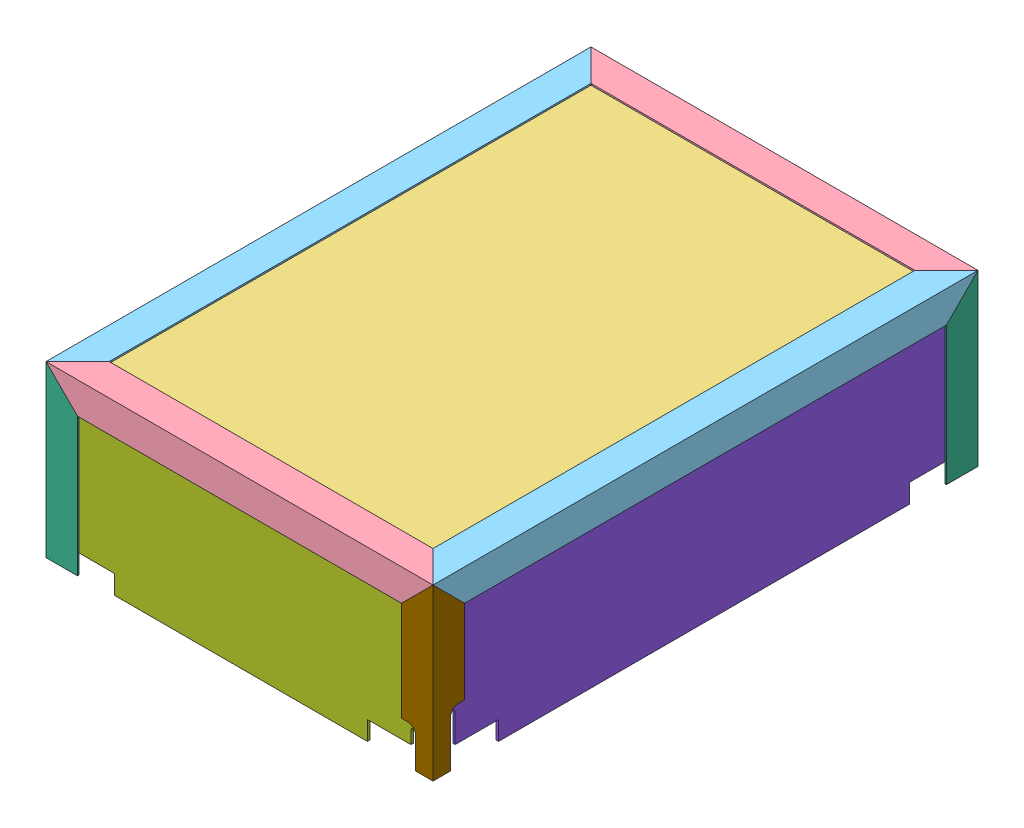
SolidWorks assembly couvercle, configuration Défaut. Lengths in mm.
Overall size (490 215 690).
13 component instances, 9 part files, 32 mates.
Components (placement in the parent):
- plaque_acrylique_680x210-2: plaque_acrylique_680x210 [Défaut] at (-694.8689 73.91 -173.3892) x (0 0 -1) z (1 0 0) size (680 210 3)
- plaque_acrylique_380x210-2: plaque_acrylique_380x210 [Défaut] at (-401.8689 73.91 -516.3892) size (480 210 3)
- plaque_acrylique_380x680-1: plaque_acrylique_380x680 [Défaut] at (-401.8689 178.91 -173.3892) x (1 0 0) z (0 1 0) size (480 680 3)
- eclisse_40x40x404_bisote_x2-1: eclisse_40x40x404_bisote_x2 [Défaut] at (-206.8689 163.7964 -498.3892) x (0 0 1) z (0 -1 0) size (40 490 40)
- eclisse_40x40x704_bisote_x2-1: eclisse_40x40x704_bisote_x2 [Défaut] at (-226.9825 163.91 -518.3892) x (0 -1 0) z (-1 0 0) size (40 690 40)
- eclisse_40x40x404_bisote_x2-2: eclisse_40x40x404_bisote_x2 [Défaut] at (-696.8689 163.7964 151.6108) x (0 0 -1) z (0 -1 0) size (40 490 40)
- eclisse_40x40x704_bisote_x2-2: eclisse_40x40x704_bisote_x2 [Défaut] at (-676.8689 163.7964 -518.3892) x (1 0 0) z (0 -1 0) size (40 690 40)
- eclisse_40x40x222_bisote_x1-1: eclisse_40x40x222_bisote_x1 [Défaut] at (-676.7552 183.91 -498.3892) x (0 0 1) z (1 0 0) size (40 215 40)
- eclisse_40x40x222_bisote_x1-2: eclisse_40x40x222_bisote_x1 [Défaut] at (-226.8689 183.91 -498.2755) x (-1 0 0) z (0 0 1) size (40 215 40)
- eclisse_40x40x222_bisote_x1-4: eclisse_40x40x222_bisote_x1 [Défaut] at (-676.8689 183.91 151.4972) x (1 0 0) z (0 0 -1) size (40 215 40)
- plaque_acrylique_380x210_Moteur-1: plaque_acrylique_380x210_Moteur [Défaut] at (-401.8689 73.91 166.6108) size (480 210 3)
- plaque_acrylique_680x210_moteur-1: plaque_acrylique_680x210_moteur [Défaut] at (-211.8689 73.91 -173.3892) x (0 0 -1) z (1 0 0) size (680 210 3)
- eclisse_40x40x222_bisote_x1_Moteur-1: eclisse_40x40x222_bisote_x1_Moteur [Défaut] at (-226.9825 183.91 151.6108) x (0 0 -1) z (-1 0 0) size (40 215 40)
Mates (geometry in assembly coordinates):
- Coïncidente1: coincident anti-aligned: plane of plaque_acrylique_380x680-1 through (-401.8689 181.91 -173.3892) normal (0 1 0); plane of eclisse_40x40x704_bisote_x2-1 through (-208.8689 181.91 171.6108) normal (0 -1 0)
- Coïncidente2: coincident anti-aligned: plane of eclisse_40x40x704_bisote_x2-1 through (-208.8689 181.91 171.6108) normal (-1 0 0); plane of plaque_acrylique_680x210_moteur-1 through (-208.8689 73.91 -173.3892) normal (1 0 0)
- Coïncidente3: coincident anti-aligned: plane of plaque_acrylique_380x210-2 through (-401.8689 73.91 -516.3892) normal (0 0 -1); plane of eclisse_40x40x404_bisote_x2-1 through (-696.8689 181.91 -516.3892) normal (0 0 1)
- Coïncidente4: coincident anti-aligned: plane of plaque_acrylique_380x680-1 through (-401.8689 181.91 -173.3892) normal (0 1 0); plane of eclisse_40x40x404_bisote_x2-1 through (-696.8689 181.91 -516.3892) normal (0 -1 0)
- Coïncidente5: coincident anti-aligned: plane of plaque_acrylique_680x210-2 through (-694.8689 73.91 -173.3892) normal (-1 0 0); plane of eclisse_40x40x704_bisote_x2-2 through (-694.8689 181.91 171.6108) normal (1 0 0)
- Coïncidente6: coincident anti-aligned: plane of plaque_acrylique_380x680-1 through (-401.8689 181.91 -173.3892) normal (0 1 0); plane of eclisse_40x40x704_bisote_x2-2 through (-694.8689 181.91 171.6108) normal (0 -1 0)
- Coïncidente7: coincident anti-aligned: plane of eclisse_40x40x404_bisote_x2-2 through (-206.8689 181.91 169.6108) normal (0 0 -1); plane of plaque_acrylique_380x210_Moteur-1 through (-401.8689 73.91 169.6108) normal (0 0 1)
- Coïncidente9: coincident anti-aligned: plane of plaque_acrylique_380x210_Moteur-1 through (-401.8689 73.91 169.6108) normal (0 0 1); plane of eclisse_40x40x222_bisote_x1_Moteur-1 through (-208.8689 -31.09 169.6108) normal (0 0 -1)
- Coïncidente10: coincident anti-aligned: plane of plaque_acrylique_680x210_moteur-1 through (-208.8689 73.91 -173.3892) normal (1 0 0); plane of eclisse_40x40x222_bisote_x1_Moteur-1 through (-208.8689 -31.09 169.6108) normal (-1 0 0)
- Coïncidente11: coincident anti-aligned: plane of plaque_acrylique_380x210-2 through (-401.8689 73.91 -516.3892) normal (0 0 -1); plane of eclisse_40x40x222_bisote_x1-2 through (-208.8689 -31.09 -516.3892) normal (0 0 1)
- Coïncidente12: coincident anti-aligned: plane of eclisse_40x40x222_bisote_x1-2 through (-208.8689 -31.09 -516.3892) normal (-1 0 0); plane of plaque_acrylique_680x210_moteur-1 through (-208.8689 73.91 -173.3892) normal (1 0 0)
- Coïncidente13: coincident anti-aligned: plane of plaque_acrylique_680x210-2 through (-694.8689 73.91 -173.3892) normal (-1 0 0); plane of eclisse_40x40x222_bisote_x1-1 through (-694.8689 -31.09 -516.3892) normal (1 0 0)
- Coïncidente14: coincident anti-aligned: plane of plaque_acrylique_380x210-2 through (-401.8689 73.91 -516.3892) normal (0 0 -1); plane of eclisse_40x40x222_bisote_x1-1 through (-694.8689 -31.09 -516.3892) normal (0 0 1)
- Coïncidente15: coincident anti-aligned: plane of eclisse_40x40x222_bisote_x1-4 through (-694.8689 -31.09 169.6108) normal (0 0 -1); plane of plaque_acrylique_380x210_Moteur-1 through (-401.8689 73.91 169.6108) normal (0 0 1)
- Coïncidente16: coincident anti-aligned: plane of plaque_acrylique_680x210-2 through (-694.8689 73.91 -173.3892) normal (-1 0 0); plane of eclisse_40x40x222_bisote_x1-4 through (-694.8689 -31.09 169.6108) normal (1 0 0)
- Coïncidente19: coincident anti-aligned: line of plaque_acrylique_380x210_Moteur-1 through (-211.8689 -7.09 166.6108) axis (0 1 0); line of plaque_acrylique_680x210_moteur-1 through (-211.8689 178.91 166.6108) axis (0 -1 0)
- Coïncidente20: coincident aligned: plane of plaque_acrylique_380x210_Moteur-1 through (-211.8689 -7.09 166.6108) normal (0 -1 0); plane of plaque_acrylique_680x210_moteur-1 through (-211.8689 -7.09 166.6108) normal (0 -1 0)
- Coïncidente21: coincident aligned: line of plaque_acrylique_680x210-2 through (-691.8689 178.91 166.6108) axis (0 -1 0); line of plaque_acrylique_380x210_Moteur-1 through (-691.8689 178.91 166.6108) axis (0 -1 0)
- Coïncidente22: coincident aligned: plane of plaque_acrylique_680x210-2 through (-694.8689 -7.09 166.6108) normal (0 -1 0); plane of plaque_acrylique_380x210_Moteur-1 through (-691.8689 -7.09 166.6108) normal (0 -1 0)
- Coïncidente23: coincident anti-aligned: line of plaque_acrylique_680x210-2 through (-691.8689 -7.09 -513.3892) axis (0 1 0); line of plaque_acrylique_380x210-2 through (-691.8689 178.91 -513.3892) axis (0 -1 0)
- Coïncidente24: coincident aligned: plane of plaque_acrylique_680x210-2 through (-694.8689 -7.09 -513.3892) normal (0 -1 0); plane of plaque_acrylique_380x210-2 through (-691.8689 -7.09 -516.3892) normal (0 -1 0)
- Coïncidente28: coincident anti-aligned: line of plaque_acrylique_380x680-1 through (-691.8689 178.91 166.6108) axis (1 0 0); line of plaque_acrylique_380x210_Moteur-1 through (-211.8689 178.91 166.6108) axis (-1 0 0)
- Coïncidente29: coincident aligned: line of plaque_acrylique_680x210-2 through (-691.8689 178.91 -513.3892) axis (0 0 1); line of plaque_acrylique_380x680-1 through (-691.8689 178.91 -513.3892) axis (0 0 1)
- Coïncidente30: coincident anti-aligned: plane of plaque_acrylique_380x680-1 through (-401.8689 181.91 -173.3892) normal (0 1 0); plane of eclisse_40x40x404_bisote_x2-2 through (-206.8689 181.91 169.6108) normal (0 -1 0)
- Coïncidente31: coincident anti-aligned: line of eclisse_40x40x404_bisote_x2-2 through (-206.8689 183.91 171.6108) axis (-0.707107 -0.707107 0); line of eclisse_40x40x222_bisote_x1_Moteur-1 through (-246.8689 143.91 171.6108) axis (0.707107 0.707107 0)
- Coïncidente32: coincident anti-aligned: line of eclisse_40x40x704_bisote_x2-1 through (-206.8689 143.91 131.6108) axis (0 0.707107 0.707107); line of eclisse_40x40x222_bisote_x1_Moteur-1 through (-206.8689 183.91 171.6108) axis (0 -0.707107 -0.707107)
- Coïncidente35: coincident anti-aligned: line of eclisse_40x40x404_bisote_x2-2 through (-656.8689 143.91 171.6108) axis (-0.707107 0.707107 0); line of eclisse_40x40x222_bisote_x1-4 through (-696.8689 183.91 171.6108) axis (0.707107 -0.707107 0)
- Coïncidente36: coincident anti-aligned: line of eclisse_40x40x704_bisote_x2-2 through (-696.8689 183.91 171.6108) axis (0 -0.707107 -0.707107); line of eclisse_40x40x222_bisote_x1-4 through (-696.8689 143.91 131.6108) axis (0 0.707107 0.707107)
- Coïncidente37: coincident anti-aligned: line of eclisse_40x40x404_bisote_x2-2 through (-696.8689 183.91 171.6108) axis (0.707107 0 -0.707107); line of eclisse_40x40x704_bisote_x2-2 through (-656.8689 183.91 131.6108) axis (-0.707107 0 0.707107)
- Coïncidente38: coincident anti-aligned: line of eclisse_40x40x404_bisote_x2-1 through (-656.8689 183.91 -478.3892) axis (-0.707107 0 -0.707107); line of eclisse_40x40x704_bisote_x2-2 through (-696.8689 183.91 -518.3892) axis (0.707107 0 0.707107)
- Coïncidente39: coincident anti-aligned: line of eclisse_40x40x704_bisote_x2-2 through (-696.8689 143.91 -478.3892) axis (0 0.707107 -0.707107); line of eclisse_40x40x222_bisote_x1-1 through (-696.8689 183.91 -518.3892) axis (0 -0.707107 0.707107)
- Coïncidente40: coincident anti-aligned: line of eclisse_40x40x404_bisote_x2-1 through (-246.8689 143.91 -518.3892) axis (0.707107 0.707107 0); line of eclisse_40x40x222_bisote_x1-2 through (-206.8689 183.91 -518.3892) axis (-0.707107 -0.707107 0)
